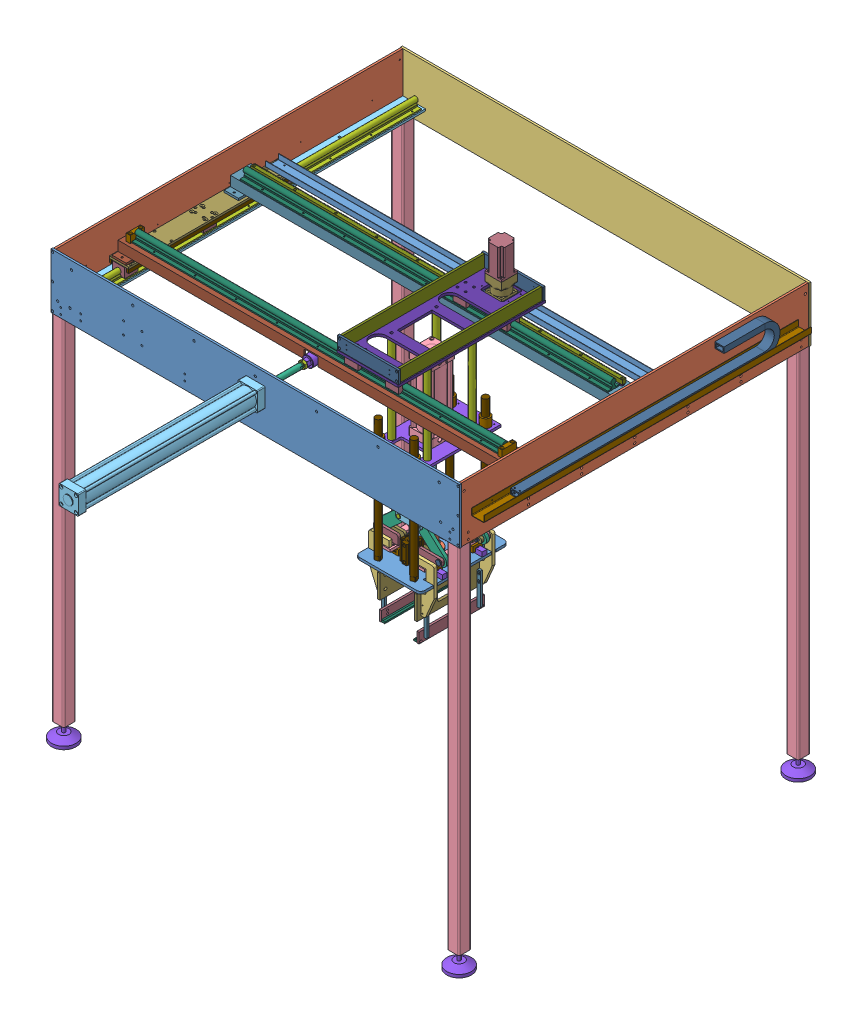
SolidWorks assembly 成品抓取排列机械手, configuration 默认. Lengths in mm.
Overall size (2113.16 2292 2692.16).
176 component instances, 69 part files, 126 mates.
Components (placement in the parent):
- 82-08-01  上线左右板-1: 82-08-01  上线左右板 [默认] at (-825.0477 550.6336 1800) size (2000 270 10)
- 82-08-02 上线前后板-2: 82-08-02 上线前后板 [默认] at (-1817.5477 550.6336 945) x (0 0 1) z (-1 0 0) size (1700 270 10)
- 82-08-03 上线左右板2-1: 82-08-03 上线左右板2 [默认] at (-825.0477 550.6336 90) x (-1 0 0) z (0 0 -1) size (2000 270 10)
- 82-08-13 支撑立柱1-1: 82-08-13 支撑立柱1 [默认<按加工>] at (-1792.5477 415.6336 115) x (0 0 1) z (1 0 0) size (60 1790 60)
- 82-08-13 支撑立柱1-3: 82-08-13 支撑立柱1 [默认<按加工>] at (142.4523 415.6336 115) x (-1 0 0) z (0 0 1) size (60 1790 60)
- 82-08-09 上线框架加强板-2: 82-08-09 上线框架加强板 [默认] at (112.4523 480.6336 945) x (0 0 -1) z (0 1 0) size (1700 110 10)
- 82-08-09 上线框架加强板-3: 82-08-09 上线框架加强板 [默认] at (-1762.5477 480.6336 945) x (0 0 1) z (0 1 0) size (1700 110 10)
- 82-08-02 上线前后板-3: 82-08-02 上线前后板 [默认] at (167.4523 550.6336 945) x (0 0 -1) z (1 0 0) size (1700 270 10)
- 82-08-05 加强筋板-12: 82-08-05 加强筋板 [默认] at (-1812.5477 475.6336 1465) x (-1 0 0) z (0 0 -1) size (60 60 10)
- 82-08-05 加强筋板-34: 82-08-05 加强筋板 [默认] at (162.4523 475.6336 1465) size (60 60 10)
- 滑轨SBR25 -1-1: 滑轨SBR25 -1 [默认] at (74.4286 478.9234 110) x (0 0 1) z (-1 0 0) size (1670 45.5 55)
- 滑轨SBR25 -1-2: 滑轨SBR25 -1 [默认] at (-1745.5714 478.9234 110) x (0 0 1) z (-1 0 0) size (1670 45.5 55)
- 调节脚Φ120-M16×165（YHBP20）-1: 调节脚Φ120-M16×165（YHBP20） [默认] at (142.4523 -1394.3664 115) x (0.999992 0 0.003912) z (-0.003912 0 0.999992) size (120 200 120)
- 调节脚Φ120-M16×165（YHBP20）-2: 调节脚Φ120-M16×165（YHBP20） [默认] at (-1792.5477 -1394.3664 115) x (0.791621 0 -0.611013) z (0.611013 0 0.791621) size (120 200 120)
- 82-08-04 坦克链线槽1-1: 82-08-04 坦克链线槽1 [默认] at (204.4523 525.6336 945) x (1 0 0) z (0 -1 0) size (64 1600 32)
- 20坦克链-2: 20坦克链 [默认] at (203.8418 539.6336 1561.8399) x (0 0 -1) z (1 0 0) size (1274 148 45)
- 82-08-14 槽钢支架1-1: 82-08-14 槽钢支架1 [默认<按加工>] at (-825.0477 613.6336 1532.1451) size (1890 58 160)
- 82-08-10 左右连接板-1: 82-08-10 左右连接板 [默认] at (-1735.0477 550.6336 1147.1451) x (1 0 0) z (0 1 0) size (95 830 10.21)
- SBR25-滑块-11: SBR25-滑块 [默认] at (-1735.0477 498.6336 1532.1451) size (60 47 65)
- SBR25-滑块-12: SBR25-滑块 [默认] at (-1735.0477 498.6336 1147.1451) size (60 47 65)
- SBR25-滑块-13: SBR25-滑块 [默认] at (-1735.0477 498.6336 762.1451) size (60 47 65)
- 82-08-10 左右连接板-2: 82-08-10 左右连接板 [默认] at (84.9523 550.6336 1147.1451) x (1 0 0) z (0 1 0) size (95 830 10.21)
- SBR25-滑块-14: SBR25-滑块 [默认] at (84.9523 498.6336 1532.1451) x (-1 0 0) z (0 0 -1) size (60 47 65)
- SBR25-滑块-15: SBR25-滑块 [默认] at (84.9523 498.6336 1147.1451) x (-1 0 0) z (0 0 -1) size (60 47 65)
- SBR25-滑块-16: SBR25-滑块 [默认] at (84.9523 498.6336 762.1451) x (-1 0 0) z (0 0 -1) size (60 47 65)
- 82-08-15 槽钢支架2-1: 82-08-15 槽钢支架2 [默认<按加工>] at (-825.0477 613.6336 982.1451) size (1890 58 160)
- 滑轨SBR25-2-3: 滑轨SBR25-2 [默认] at (-1725.0477 606.9234 962.6688) size (1800 45.5 55)
- 滑轨SBR25-2-4: 滑轨SBR25-2 [默认] at (-1725.0477 606.9234 1492.6688) size (1800 45.5 55)
- 82-06-00-200机械手装配体-翻转前抓取1-2: 82-06-00-200机械手装配体-翻转前抓取1 [默认] at (-1138.3737 644.7541 1170.3657) x (0 0 -1) z (1 0 0) size (720 1262.5 374.38)
  - 82-06-01  直线滑块固定板-1: 82-06-01  直线滑块固定板 [默认] at (-1.7794 70.8795 450) size (696 60 10)
  - 82-06-03  移动主板3-1: 82-06-03  移动主板3 [默认] at (-1.7794 34.8795 590) x (-1 0 0) z (0 1 0) size (720 300 12)
  - 82-06-17  抓取导向杆3-1: 82-06-17  抓取导向杆3 [默认] at (-221.7794 -585.1205 502.5) x (0 1 0) z (0.328486 0 0.944509) size (630 30 30)
  - 82-06-17  抓取导向杆3-2: 82-06-17  抓取导向杆3 [默认] at (-221.7794 -585.1205 677.5) x (0 1 0) z (0.328486 0 0.944509) size (630 30 30)
  - 82-06-17  抓取导向杆3-3: 82-06-17  抓取导向杆3 [默认] at (128.2206 -585.1205 502.5) x (0 1 0) z (0.328486 0 0.944509) size (630 30 30)
  - 82-06-17  抓取导向杆3-4: 82-06-17  抓取导向杆3 [默认] at (128.2206 -585.1205 677.5) x (0 1 0) z (0.328486 0 0.944509) size (630 30 30)
  - 82-06-14 抓取气缸固定板-1: 82-06-14 抓取气缸固定板 [默认] at (-46.7794 -891.1205 590) x (1 0 0) z (0 -1 0) size (430 320 12)
  - 82-06-06 升降连接法兰-1: 82-06-06 升降连接法兰 [默认] at (-46.7794 -707.1205 590) x (0 -1 0) z (-1 0 0) size (178 90 90)
  - 82-06-11  抓取气缸筋板-4: 82-06-11  抓取气缸筋板 [默认] at (95.7206 -837.1205 649.3691) x (0 0 1) z (-1 0 0) size (100 240 15)
  - 82-06-13  夹板连接板-1: 82-06-13  夹板连接板 [默认] at (-46.7794 -849.1205 674.3691) x (1 0 0) z (0 1 0) size (310 70 12)
  - 82-06-09 横梁块-1: 82-06-09 横梁块 [默认] at (50.7206 -711.1205 590) x (0 0 1) z (0 -1 0) size (120 40 30)
  - 82-06-07 抓取连接板-1: 82-06-07 抓取连接板 [默认] at (43.2206 -760.1205 688.4345) x (0 -0.675862 0.737028) z (1 0 0) size (195 50 15)
  - 82-06-19 上拉杆-1: 82-06-19 上拉杆 [默认] at (73.7206 -711.1205 635) x (-1 0 0) z (0 -0.924225 -0.381849) size (43 17 17)
  - 82-06-07 抓取连接板-3: 82-06-07 抓取连接板 [默认] at (43.2206 -760.1205 491.5655) x (0 -0.675862 -0.737028) z (1 0 0) size (195 50 15)
  - 82-06-11  抓取气缸筋板-6: 82-06-11  抓取气缸筋板 [默认] at (95.7206 -837.1205 530.6309) x (0 0 -1) z (1 0 0) size (100 240 15)
  - 82-06-13  夹板连接板-2: 82-06-13  夹板连接板 [默认] at (-46.7794 -837.1205 505.6309) x (1 0 0) z (0 -1 0) size (310 70 12)
  - 82-06-19 上拉杆-2: 82-06-19 上拉杆 [默认] at (73.7206 -711.1205 545) x (-1 0 0) z (0 -0.924225 0.381849) size (43 17 17)
  - 82-06-11  抓取气缸筋板-9: 82-06-11  抓取气缸筋板 [默认] at (-189.2794 -837.1205 649.3691) x (0 0 1) z (-1 0 0) size (100 240 15)
  - 82-06-07 抓取连接板-4: 82-06-07 抓取连接板 [默认] at (-136.7794 -760.1205 688.4345) x (0 0.675862 -0.737028) z (-1 0 0) size (195 50 15)
  - 82-06-07 抓取连接板-5: 82-06-07 抓取连接板 [默认] at (-136.7794 -760.1205 491.5655) x (0 0.675862 0.737028) z (-1 0 0) size (195 50 15)
  - 82-06-11  抓取气缸筋板-8: 82-06-11  抓取气缸筋板 [默认] at (-189.2794 -837.1205 530.6309) x (0 0 -1) z (1 0 0) size (100 240 15)
  - 82-06-09 横梁块-2: 82-06-09 横梁块 [默认] at (-144.2794 -711.1205 590) x (0 0 1) z (0 1 0) size (120 40 30)
  - 82-06-19 上拉杆-3: 82-06-19 上拉杆 [默认] at (-167.2794 -711.1205 635) x (1 0 0) z (0 -0.924225 -0.381849) size (43 17 17)
  - 82-06-19 上拉杆-4: 82-06-19 上拉杆 [默认] at (-167.2794 -711.1205 545) x (1 0 0) z (0 -0.924225 0.381849) size (43 17 17)
  - 00-HGW25滑轨长125-1: 00-HGW25滑轨长125 [默认] at (50.7206 -874.1205 750) x (0 0 -1) z (1 0 0) size (125 22 23)
  - 00-HGW25滑块-1: 00-HGW25滑块 [默认] at (50.7206 -850.1205 674.3691) size (70 29.5 84)
  - 82-06-12  拉杆-1: 82-06-12  拉杆 [默认] at (75.2206 -809.1205 741.8691) x (-1 0 0) z (0 -0.506926 -0.86199) size (58 22 22)
  - 82-06-12  拉杆-2: 82-06-12  拉杆 [默认] at (75.2206 -809.1205 438.1309) x (-1 0 0) z (0 -0.506926 0.86199) size (58 22 22)
  - 00-镜向HGW25滑轨长115-2: 00-镜向HGW25滑轨长115 [默认] at (50.7206 -874.1205 430) x (0 0 1) z (-1 0 0) size (125 22 23)
  - 00-HGW25滑块-2: 00-HGW25滑块 [默认] at (50.7206 -850.1205 505.6309) size (70 29.5 84)
  - 00-HGW25滑块-3: 00-HGW25滑块 [默认] at (-144.2794 -850.1205 674.3691) x (-1 0 0) z (0 0 -1) size (70 29.5 84)
  - 00-HGW25滑轨长125-3: 00-HGW25滑轨长125 [默认] at (-144.2794 -874.1205 750) x (0 0 -1) z (1 0 0) size (125 22 23)
  - 82-06-12  拉杆-3: 82-06-12  拉杆 [默认] at (-168.7794 -809.1205 741.8691) x (1 0 0) z (0 -0.506926 -0.86199) size (58 22 22)
  - 82-06-12  拉杆-4: 82-06-12  拉杆 [默认] at (-168.7794 -809.1205 438.1309) x (1 0 0) z (0 -0.506926 0.86199) size (58 22 22)
  - 00-HGW25滑块-4: 00-HGW25滑块 [默认] at (-144.2794 -850.1205 505.6309) x (-1 0 0) z (0 0 -1) size (70 29.5 84)
  - 00-镜向HGW25滑轨长115-4: 00-镜向HGW25滑轨长115 [默认] at (-144.2794 -874.1205 430) x (0 0 1) z (-1 0 0) size (125 22 23)
  - 82-06-08 滑块转角锁板-1: 82-06-08 滑块转角锁板 [默认] at (35.2206 -837.1205 636.8691) x (0 0 1) z (-1 0 0) size (120 40 12)
  - 82-06-18 滑块转角前锁板-1: 82-06-18 滑块转角前锁板 [默认] at (66.2206 -837.1205 636.8691) x (0 0 1) z (-1 0 0) size (120 44 12)
  - 82-06-08 滑块转角锁板-3: 82-06-08 滑块转角锁板 [默认] at (35.2206 -837.1205 543.1309) x (0 0 -1) z (1 0 0) size (120 40 12)
  - 82-06-18 滑块转角前锁板-2: 82-06-18 滑块转角前锁板 [默认] at (66.2206 -837.1205 543.1309) x (0 0 -1) z (1 0 0) size (120 44 12)
  - 82-06-18 滑块转角前锁板-3: 82-06-18 滑块转角前锁板 [默认] at (-159.7794 -837.1205 636.8691) x (0 0 1) z (-1 0 0) size (120 44 12)
  - 82-06-08 滑块转角锁板-4: 82-06-08 滑块转角锁板 [默认] at (-128.7794 -837.1205 636.8691) x (0 0 1) z (-1 0 0) size (120 40 12)
  - 82-06-18 滑块转角前锁板-4: 82-06-18 滑块转角前锁板 [默认] at (-159.7794 -837.1205 543.1309) x (0 0 -1) z (1 0 0) size (120 44 12)
  - 82-06-08 滑块转角锁板-5: 82-06-08 滑块转角锁板 [默认] at (-128.7794 -837.1205 543.1309) x (0 0 -1) z (1 0 0) size (120 40 12)
  - 00-ACQ50x50SB(0)+()-1: 00-ACQ50x50SB(0)+() [默认] at (50.7206 -794.6205 590) x (0 -1 0) z (1 0 0) size (174 64 71) (flexible)
    - 00-ACQS-50x5050_b-1: 00-ACQS-50x5050_b [默认] x (1 0 0) z (0 -1 0) size (90.5 71 64)
    - 00-ACQS-50x50-B_50r-1: 00-ACQS-50x50-B_50r [默认] at (-50 0 0) size (115 50 50)
    - 00-ACQ 50_Nut-1: 00-ACQ 50_Nut [默认] at (-57.5 0 0) x (-1 0 0) z (0 0.341797 -0.939774) size (11 34.29 27)
  - 82-06-10 上拉杆隔套-5: 82-06-10 上拉杆隔套 [默认] at (55.7206 -711.1205 635) x (0 0.442922 0.89656) z (1 0 0) size (18 18 3)
  - 82-06-10 上拉杆隔套-6: 82-06-10 上拉杆隔套 [默认] at (-152.2794 -711.1205 635) x (0 0.442922 0.89656) z (1 0 0) size (18 18 3)
  - 82-06-10 上拉杆隔套-7: 82-06-10 上拉杆隔套 [默认] at (58.7206 -711.1205 545) x (0 0.442922 -0.89656) z (-1 0 0) size (18 18 3)
  - 82-06-10 上拉杆隔套-8: 82-06-10 上拉杆隔套 [默认] at (-149.2794 -711.1205 545) x (0 0.442922 -0.89656) z (-1 0 0) size (18 18 3)
  - 镜向00-ACQ50x50SB(0)+()-3: 镜向00-ACQ50x50SB(0)+() [默认] at (-144.2794 -794.6205 590) x (0 -1 0) z (1 0 0) size (174 64 71) (flexible)
    - 镜向00-ACQS-50x5050_b-1: 镜向00-ACQS-50x5050_b [默认] x (1 0 0) z (0 1 0) size (90.5 71 64)
    - 镜向00-ACQS-50x50-B_50r-1: 镜向00-ACQS-50x50-B_50r [默认] at (-50 0 0) size (115 50 50)
    - 镜向00-ACQ 50_Nut-1: 镜向00-ACQ 50_Nut [默认] at (-57.5 0 0) x (-1 0 0) z (0 -0.341797 -0.939774) size (11 34.29 27)
  - GB／T276-94深沟球轴承6201-2Z-1: GB／T276-94深沟球轴承6201-2Z [默认] at (50.7206 -809.1205 438.1309) x (1 0 0) z (0 0.587051 -0.80955) size (10 32 32)
  - GB／T276-94深沟球轴承6201-2Z-2: GB／T276-94深沟球轴承6201-2Z [默认] at (-144.2794 -809.1205 438.1309) x (1 0 0) z (0 0.353964 0.935259) size (10 32 32)
  - JSI100x250S(000)+()-2: JSI100x250S(000)+() [默认] at (-46.7794 -405.1205 590) x (0 1 0) z (0 0 1) size (690 114 114)
    - JSI-100x250-S- (0) c-1: JSI-100x250-S- (0) c [默认] at origin size (388 114 114)
    - JSI JSID JSIJ POLE 100JSI2500-1: JSI JSID JSIJ POLE 100JSI2500 [默认] at (-270 0 0) x (0 0 -1) z (-1 0 0) size (99 99 401)
    - JSI-100-M26x1_5 - Nut-1: JSI-100-M26x1_5 - Nut [默认] at (-302 0 0) size (13 41.57 36)
  - 82-06-04 气缸支撑杆-1: 82-06-04 气缸支撑杆 [默认] at (63.2206 -188.1205 677.5) x (0.271774 0 0.962361) z (0 1 0) size (30 30 434)
  - 82-06-04 气缸支撑杆-4: 82-06-04 气缸支撑杆 [默认] at (63.2206 -188.1205 502.5) x (-0.824959 0 0.565193) z (0 1 0) size (30 30 434)
  - 82-06-05 二层导向板2-1: 82-06-05 二层导向板2 [默认] at (-46.7794 -411.1205 590) x (1 0 0) z (0 1 0) size (430 245 12)
  - 82-06-04 气缸支撑杆-5: 82-06-04 气缸支撑杆 [默认] at (-156.7794 -188.1205 677.5) x (-0.271774 0 0.962361) z (0 -1 0) size (30 30 434)
  - 82-06-04 气缸支撑杆-6: 82-06-04 气缸支撑杆 [默认] at (-156.7794 -188.1205 502.5) x (0.824959 0 0.565193) z (0 -1 0) size (30 30 434)
  - 直线轴承LMH-30UU-11: 直线轴承LMH-30UU [默认] at (-221.7794 -427.1205 502.5) x (0 1 0) z (0 0 1) size (64 74 51)
  - 直线轴承LMH-30UU-12: 直线轴承LMH-30UU [默认] at (128.2206 -427.1205 502.5) x (0 1 0) z (0 0 1) size (64 74 51)
  - 直线轴承LMH-30UU-13: 直线轴承LMH-30UU [默认] at (-221.7794 -427.1205 677.5) x (0 1 0) z (0 0 1) size (64 74 51)
  - 直线轴承LMH-30UU-14: 直线轴承LMH-30UU [默认] at (128.2206 -427.1205 677.5) x (0 1 0) z (0 0 1) size (64 74 51)
  - 盖子（120AH）-1: 盖子（120AH） [默认] at (-250.2794 -1134.1205 503.5) x (1 0 0) z (0 -1 0) size (407 173 55.85) (hidden)
  - 00-电池壳120-2: 00-电池壳120 [默认] at (155.7206 -1149.1205 503.5) x (-1 0 0) z (0 1 0) size (405 173 190) (hidden)
  - 82-06-02 位移左端板-3: 82-06-02 位移左端板 [默认] at (-354.7794 100.8795 740) x (0 0 -1) z (1 0 0) size (300 60 10)
  - 82-06-01  直线滑块固定板-2: 82-06-01  直线滑块固定板 [默认] at (-1.7794 70.8795 730) size (696 60 10)
  - 82-06-02 位移左端板-4: 82-06-02 位移左端板 [默认] at (351.2206 100.8795 440) x (0 0 1) z (-1 0 0) size (300 60 10)
  - GB／T276-94深沟球轴承6201-2Z-3: GB／T276-94深沟球轴承6201-2Z [默认] at (50.7206 -711.1205 635) size (10 32 32)
  - 82-06-10 上拉杆隔套-9: 82-06-10 上拉杆隔套 [默认] at (42.7206 -711.1205 635) x (0 0.909511 -0.41568) z (1 0 0) size (18 18 3)
  - 82-06-10 上拉杆隔套-10: 82-06-10 上拉杆隔套 [默认] at (45.7206 -711.1205 545) x (0 0.909511 0.41568) z (-1 0 0) size (18 18 3)
  - GB／T276-94深沟球轴承6201-2Z-4: GB／T276-94深沟球轴承6201-2Z [默认] at (50.7206 -711.1205 545) size (10 32 32)
  - GB／T276-94深沟球轴承6201-2Z-5: GB／T276-94深沟球轴承6201-2Z [默认] at (-144.2794 -711.1205 635) x (-1 0 0) z (0 0 -1) size (10 32 32)
  - 82-06-10 上拉杆隔套-11: 82-06-10 上拉杆隔套 [默认] at (-139.2794 -711.1205 635) x (0 0.909511 -0.41568) z (1 0 0) size (18 18 3)
  - GB／T276-94深沟球轴承6201-2Z-6: GB／T276-94深沟球轴承6201-2Z [默认] at (-144.2794 -711.1205 545) x (-1 0 0) z (0 0 -1) size (10 32 32)
  - 82-06-10 上拉杆隔套-12: 82-06-10 上拉杆隔套 [默认] at (-136.2794 -711.1205 545) x (0 0.909511 0.41568) z (-1 0 0) size (18 18 3)
  - 82-06-20 上拉杆隔套2-1: 82-06-20 上拉杆隔套2 [默认] at (41.2206 -809.1205 438.1309) x (0 0.909511 -0.41568) z (1 0 0) size (18 18 4.5)
  - GB／T276-94深沟球轴承6201-2Z-7: GB／T276-94深沟球轴承6201-2Z [默认] at (50.7206 -809.1205 741.8691) x (1 0 0) z (0 -0.587051 -0.80955) size (10 32 32)
  - 82-06-20 上拉杆隔套2-2: 82-06-20 上拉杆隔套2 [默认] at (45.7206 -809.1205 741.8691) x (0 0.909511 0.41568) z (-1 0 0) size (18 18 4.5)
  - GB／T276-94深沟球轴承6201-2Z-8: GB／T276-94深沟球轴承6201-2Z [默认] at (-144.2794 -809.1205 741.8691) x (-1 0 0) z (0 0.587051 0.80955) size (10 32 32)
  - 82-06-20 上拉杆隔套2-3: 82-06-20 上拉杆隔套2 [默认] at (-134.7794 -809.1205 741.8691) x (0 0.909511 0.41568) z (-1 0 0) size (18 18 4.5)
  - GB／T276-94深沟球轴承6201-2Z-9: GB／T276-94深沟球轴承6201-2Z [默认] at (-144.2794 -809.1205 438.1309) x (-1 0 0) z (0 -0.587051 0.80955) size (10 32 32)
  - 82-06-20 上拉杆隔套2-4: 82-06-20 上拉杆隔套2 [默认] at (-139.2794 -809.1205 438.1309) x (0 0.909511 -0.41568) z (1 0 0) size (18 18 4.5)
  - 82-06-15  锁紧板2-1: 82-06-15  锁紧板2 [默认] at (-46.7794 -1004.6205 686.8691) x (-1 0 0) z (0 0 -1) size (340 115 12)
  - 82-06-21 夹壳定位块1-4: 82-06-21 夹壳定位块1 [默认] at (113.2206 -1161.6205 676.8691) x (0 0 1) z (-1 0 0) size (10 50 320)
  - 82-06-16 卡盖调节板-2: 82-06-16 卡盖调节板 [默认] at (-171.7794 -1147.1205 701.8691) x (0 1 0) z (-1 0 0) size (160 15 10)
  - 82-06-16 卡盖调节板-3: 82-06-16 卡盖调节板 [默认] at (88.2206 -1147.1205 701.8691) x (0 1 0) z (-1 0 0) size (160 15 10)
  - 82-06-16 卡盖调节板-4: 82-06-16 卡盖调节板 [默认] at (78.2206 -1147.1205 478.1309) x (0 1 0) z (1 0 0) size (160 15 10)
  - 82-06-16 卡盖调节板-5: 82-06-16 卡盖调节板 [默认] at (-181.7794 -1147.1205 478.1309) x (0 1 0) z (1 0 0) size (160 15 10)
  - 82-06-21 夹壳定位块1-5: 82-06-21 夹壳定位块1 [默认] at (-206.7794 -1161.6205 503.1309) x (0 0 -1) z (1 0 0) size (10 50 320)
  - 82-06-22 夹壳定位块2-3: 82-06-22 夹壳定位块2 [默认] at (113.2206 -1159.6205 676.8691) x (0 1 0) z (-1 0 0) size (10 16 320)
  - 82-06-22 夹壳定位块2-4: 82-06-22 夹壳定位块2 [默认] at (-206.7794 -1159.6205 503.1309) x (0 1 0) z (1 0 0) size (10 16 320)
  - 82-06-15  锁紧板2-3: 82-06-15  锁紧板2 [默认] at (-46.7794 -1004.6205 493.1309) size (340 115 12)
- SBR25-滑块-17: SBR25-滑块 [默认] at (-648.3737 626.6336 1482.1451) x (0 0 -1) z (1 0 0) size (60 47 65)
- SBR25-滑块-18: SBR25-滑块 [默认] at (-448.3737 626.6336 1482.1451) x (0 0 -1) z (1 0 0) size (60 47 65)
- SBR25-滑块-19: SBR25-滑块 [默认] at (-648.3737 626.6336 952.1451) x (0 0 -1) z (1 0 0) size (60 47 65)
- SBR25-滑块-20: SBR25-滑块 [默认] at (-448.3737 626.6336 952.1451) x (0 0 -1) z (1 0 0) size (60 47 65)
- 2M齿条2-1: 2M齿条2 [默认] at (-825.0477 620.1336 918.1451) x (0 1 0) z (-1 0 0) size (20 20 1820)
- 82-08-12 齿条垫圈-10: 82-08-12 齿条垫圈 [默认] at (74.9523 616.8836 911.1451) x (0.980798 0 -0.195024) z (0.195024 0 0.980798) size (18 6.5 18)
- 82-08-12 齿条垫圈-11: 82-08-12 齿条垫圈 [默认] at (-125.0477 616.8836 911.1451) x (0.980798 0 -0.195024) z (0.195024 0 0.980798) size (18 6.5 18)
- 82-08-12 齿条垫圈-12: 82-08-12 齿条垫圈 [默认] at (-325.0477 616.8836 911.1451) x (0.980798 0 -0.195024) z (0.195024 0 0.980798) size (18 6.5 18)
- 82-08-12 齿条垫圈-13: 82-08-12 齿条垫圈 [默认] at (-525.0477 616.8836 911.1451) x (0.980798 0 -0.195024) z (0.195024 0 0.980798) size (18 6.5 18)
- 82-08-12 齿条垫圈-14: 82-08-12 齿条垫圈 [默认] at (-725.0477 616.8836 911.1451) x (0.980798 0 -0.195024) z (0.195024 0 0.980798) size (18 6.5 18)
- 82-08-12 齿条垫圈-15: 82-08-12 齿条垫圈 [默认] at (-925.0477 616.8836 911.1451) x (0.980798 0 -0.195024) z (0.195024 0 0.980798) size (18 6.5 18)
- 82-08-12 齿条垫圈-16: 82-08-12 齿条垫圈 [默认] at (-1125.0477 616.8836 911.1451) x (0.980798 0 -0.195024) z (0.195024 0 0.980798) size (18 6.5 18)
- 82-08-12 齿条垫圈-17: 82-08-12 齿条垫圈 [默认] at (-1325.0477 616.8836 911.1451) x (0.980798 0 -0.195024) z (0.195024 0 0.980798) size (18 6.5 18)
- 82-08-12 齿条垫圈-18: 82-08-12 齿条垫圈 [默认] at (-1525.0477 616.8836 911.1451) x (0.980798 0 -0.195024) z (0.195024 0 0.980798) size (18 6.5 18)
- 82-08-12 齿条垫圈-19: 82-08-12 齿条垫圈 [默认] at (-1725.0477 616.8836 911.1451) x (0.980798 0 -0.195024) z (0.195024 0 0.980798) size (18 6.5 18)
- 82-08-11 左右连接加强板-1: 82-08-11 左右连接加强板 [默认] at (-1693.5477 536.6336 1147.1451) x (0 1 0) z (-1 0 0) size (18 830 11)
- 82-08-16 拖链折板-1: 82-08-16 拖链折板 [默认] at (-825.0477 557.6336 772.1451) x (0 0 1) z (-1 0 0) size (64 27 1900)
- 82-08-08 坦克链连接块-2: 82-08-08 坦克链连接块 [默认] at (-653.3737 732.6336 812.1451) x (0 -1 0) z (1 0 0) size (37 62 22)
- 82-08-11 左右连接加强板-2: 82-08-11 左右连接加强板 [默认] at (-1776.5477 536.6336 1147.1451) x (0 1 0) z (-1 0 0) size (18 830 11)
- 82-08-11 左右连接加强板-3: 82-08-11 左右连接加强板 [默认] at (43.4523 536.6336 1147.1451) x (0 1 0) z (-1 0 0) size (18 830 11)
- 82-08-11 左右连接加强板-4: 82-08-11 左右连接加强板 [默认] at (126.4523 536.6336 1147.1451) x (0 1 0) z (-1 0 0) size (18 830 11)
- 82-08-05 加强筋板-30: 82-08-05 加强筋板 [默认] at (-1812.5477 475.6336 1205) x (-1 0 0) z (0 0 -1) size (60 60 10)
- 82-08-05 加强筋板-31: 82-08-05 加强筋板 [默认] at (-1812.5477 475.6336 945) x (-1 0 0) z (0 0 -1) size (60 60 10)
- 82-08-05 加强筋板-32: 82-08-05 加强筋板 [默认] at (-1812.5477 475.6336 685) x (-1 0 0) z (0 0 -1) size (60 60 10)
- 82-08-05 加强筋板-33: 82-08-05 加强筋板 [默认] at (-1812.5477 475.6336 425) x (-1 0 0) z (0 0 -1) size (60 60 10)
- 82-08-05 加强筋板-35: 82-08-05 加强筋板 [默认] at (162.4523 475.6336 1205) size (60 60 10)
- 82-08-05 加强筋板-36: 82-08-05 加强筋板 [默认] at (162.4523 475.6336 945) size (60 60 10)
- 82-08-05 加强筋板-37: 82-08-05 加强筋板 [默认] at (162.4523 475.6336 685) size (60 60 10)
- 82-08-05 加强筋板-38: 82-08-05 加强筋板 [默认] at (162.4523 475.6336 425) size (60 60 10)
- 82-08-13 支撑立柱1-5: 82-08-13 支撑立柱1 [默认<按加工>] at (142.4523 415.6336 1775) x (0 0 -1) z (-1 0 0) size (60 1790 60)
- 82-08-13 支撑立柱1-6: 82-08-13 支撑立柱1 [默认<按加工>] at (-1792.5477 415.6336 1775) x (1 0 0) z (0 0 -1) size (60 1790 60)
- 调节脚Φ120-M16×165（YHBP20）-3: 调节脚Φ120-M16×165（YHBP20） [默认] at (142.4523 -1394.3664 1775) x (0.999992 0 -0.003912) z (0.003912 0 0.999992) size (120 200 120)
- 调节脚Φ120-M16×165（YHBP20）-4: 调节脚Φ120-M16×165（YHBP20） [默认] at (-1792.5477 -1394.3664 1775) x (0.791621 0 0.611013) z (-0.611013 0 0.791621) size (120 200 120)
- 82-08-17 前后加强侧板-1: 82-08-17 前后加强侧板 [默认] at (-825.0477 645.6336 1782.5) x (1 0 0) z (0 -1 0) size (1975 25 14)
- 82-08-07 齿轮连接头-1: 82-08-07 齿轮连接头 [默认] at (-548.3737 625.1336 877.1451) x (0 0 -1) z (-1 0 0) size (21 7.5 25)
- JSI80x800S(000)+()-1: JSI80x800S(000)+() [默认] at (-825.0477 578.6336 1805) x (0 0 1) z (-1 0 0) size (1177.35 95 95) (flexible)
  - JSI-80x800-S- (0) c-1: JSI-80x800-S- (0) c [默认] at origin size (938 95 95)
  - JSI JSID JSIJ POLE 80JSI8000-1: JSI JSID JSIJ POLE 80JSI8000 [默认] at (-207.3549 0 0) x (0 0 -1) z (-1 0 0) size (79 79 951.5)
  - JSI-80-M22x1_5 - Nut-1: JSI-80-M22x1_5 - Nut [默认] at (-239.3549 0 0) size (13 36.95 32)
- F-M22X150F-1: F-M22X150F [默认] at (-825.0477 578.6336 1457.6451) x (-0.195458 -0.980712 0) z (0 0 1) size (53 53 108)
- 82-08-18 限位挡块-1: 82-08-18 限位挡块 [默认] at (-1735.0477 631.1336 1482.1451) x (0 0 1) z (-1 0 0) size (70 35 20)
- 82-08-18 限位挡块-2: 82-08-18 限位挡块 [默认] at (84.9523 631.1336 1482.1451) x (0 0 1) z (-1 0 0) size (70 35 20)
- 82-08-06 电机安装板2-1: 82-08-06 电机安装板2 [默认] at (-548.3737 668.6336 877.1451) x (0 0 1) z (0 -1 0) size (90 150 10)
- 82-08-19 圆柱齿轮23×2-3: 82-08-19 圆柱齿轮23×2 [默认] at (-548.3737 620.1336 877.1451) x (-0.457191 0 -0.889369) z (0 1 0) size (49.96 49.85 35)
- FA80-10 利明减速机-1: FA80-10 利明减速机 [默认] at (-548.3737 757.6336 877.1451) x (1 0 0) z (0 -1 0) size (80 80 132.5)
- JSMA-SC08ABA01-1: JSMA-SC08ABA01 [默认] at (-548.3737 757.6336 877.1451) x (1 0 0) z (0 1 0) size (80 80 140)
Mates (geometry in assembly coordinates):
- 同心3: concentric aligned: cylinder of 82-08-01  上线左右板-1 through (-1817.5477 675.6336 1805) axis (0 0 1) radius 3.3; cylinder of 82-08-02 上线前后板-2 through (-1817.5477 675.6336 1795) axis (0 0 1) radius 2.5
- 重合2: coincident anti-aligned: plane of 82-08-01  上线左右板-1 through (-825.0477 550.6336 1795) normal (0 0 -1); plane of 82-08-02 上线前后板-2 through (-1822.5477 415.6336 1795) normal (0 0 1)
- 重合3: coincident anti-aligned: plane of 82-08-02 上线前后板-2 through (-1822.5477 415.6336 95) normal (0 0 -1); plane of 82-08-03 上线左右板2-1 through (-825.0477 550.6336 95) normal (0 0 1)
- 同心5: concentric aligned: cylinder of 82-08-02 上线前后板-2 through (-1817.5477 675.6336 95) axis (0 0 -1) radius 2.5; cylinder of 82-08-03 上线左右板2-1 through (-1817.5477 675.6336 85) axis (0 0 -1) radius 3.3
- 同心27: concentric aligned: cylinder of 82-08-01  上线左右板-1 through (-1817.5477 425.6336 1805) axis (0 0 1) radius 5.5; circle of 82-08-02 上线前后板-2
- 重合92: coincident anti-aligned: plane of 82-08-01  上线左右板-1 through (-825.0477 550.6336 1795) normal (0 0 -1); plane of 82-08-09 上线框架加强板-2 through (162.4523 485.6336 1795) normal (0 0 1)
- 重合93: coincident anti-aligned: plane of 82-08-02 上线前后板-2 through (-1812.5477 550.6336 945) normal (1 0 0); plane of 82-08-09 上线框架加强板-3 through (-1812.5477 485.6336 95) normal (-1 0 0)
- 同心100: concentric aligned: cylinder of 82-08-03 上线左右板2-1 through (167.4523 425.6336 85) axis (0 0 -1) radius 3.3; cylinder of 82-08-02 上线前后板-3 through (167.4523 425.6336 95) axis (0 0 -1) radius 2.5
- 重合95: coincident anti-aligned: plane of 82-08-03 上线左右板2-1 through (-825.0477 550.6336 95) normal (0 0 1); plane of 82-08-02 上线前后板-3 through (172.4523 415.6336 95) normal (0 0 -1)
- 同心101: concentric aligned: cylinder of 82-08-03 上线左右板2-1 through (167.4523 675.6336 85) axis (0 0 -1) radius 5.5; cylinder of 82-08-02 上线前后板-3 through (167.4523 675.6336 95) axis (0 0 -1) radius 2.5
- 同心102: concentric aligned: cylinder of 82-08-03 上线左右板2-1 through (167.4523 550.6336 85) axis (0 0 -1) radius 5.5; cylinder of 82-08-02 上线前后板-3 through (167.4523 550.6336 95) axis (0 0 -1) radius 2.5
- 同心103: concentric aligned: cylinder of 82-08-01  上线左右板-1 through (167.4523 675.6336 1805) axis (0 0 1) radius 5.5; circle of 82-08-02 上线前后板-3
- 重合101: coincident anti-aligned: plane of 82-08-02 上线前后板-2 through (-1812.5477 550.6336 945) normal (1 0 0); plane of 82-08-05 加强筋板-12 through (-1812.5477 415.6336 1460) normal (-1 0 0)
- 重合103: coincident anti-aligned: plane of 82-08-02 上线前后板-3 through (162.4523 550.6336 945) normal (-1 0 0); plane of 82-08-05 加强筋板-34 through (162.4523 415.6336 1470) normal (1 0 0)
- 重合104: coincident anti-aligned: plane of 82-08-09 上线框架加强板-2 through (112.4523 475.6336 945) normal (0 -1 0); plane of 82-08-05 加强筋板-34 through (162.4523 475.6336 1470) normal (0 1 0)
- 重合173: coincident anti-aligned: plane of 82-08-09 上线框架加强板-2 through (112.4523 485.6336 945) normal (0 1 0); plane of 滑轨SBR25 -1-1 through (112.4523 485.6336 1780) normal (0 -1 0)
- 重合227: coincident anti-aligned: plane of 82-08-09 上线框架加强板-3 through (-1762.5477 485.6336 945) normal (0 1 0); plane of 滑轨SBR25 -1-2 through (-1707.5477 485.6336 1780) normal (0 -1 0)
- 同心297: concentric aligned: cylinder of 82-08-09 上线框架加强板-3 through (-1752.5477 485.6336 1745) axis (0 1 0) radius 2.5; cylinder of 滑轨SBR25 -1-2 through (-1752.5477 491.6336 1745) axis (0 1 0) radius 3.3
- 同心298: concentric aligned: cylinder of 82-08-09 上线框架加强板-2 through (67.4523 485.6336 145) axis (0 1 0) radius 2.5; cylinder of 滑轨SBR25 -1-1 through (67.4523 491.6336 145) axis (0 1 0) radius 3.3
- 重合238: coincident aligned: plane of 调节脚Φ120-M16×165（YHBP20）-1 through (142.4523 -1394.3664 115) normal (0 -1 0); plane of 调节脚Φ120-M16×165（YHBP20）-2 through (-1792.5477 -1394.3664 115) normal (0 -1 0)
- 重合252: coincident anti-aligned: plane of 82-08-02 上线前后板-3 through (172.4523 550.6336 945) normal (1 0 0); plane of 82-08-04 坦克链线槽1-1 through (172.4523 555.6336 1745) normal (-1 0 0)
- 同心329: concentric anti-aligned: circle of 82-08-02 上线前后板-3; cylinder of 82-08-04 坦克链线槽1-1 through (172.4523 540.6336 1645) axis (-1 0 0) radius 2.75
- 同心330: concentric anti-aligned: cylinder of 82-08-02 上线前后板-3 through (172.4523 540.6336 1295) axis (1 0 0) radius 2.1; circle of 82-08-04 坦克链线槽1-1
- 重合253: coincident anti-aligned: plane of 82-08-04 坦克链线槽1-1 through (177.4523 525.6336 1745) normal (0 1 0); plane of 20坦克链-2 through (226.3418 525.6336 1561.8399) normal (0 -1 0)
- 同心337: concentric aligned: cylinder of 滑轨SBR25 -1-2 through (-1735.0477 518.6336 1780) axis (0 0 -1) radius 12.5; cylinder of SBR25-滑块-11 through (-1735.0477 518.6336 1564.6451) axis (0 0 -1) radius 12.5
- 重合256: coincident anti-aligned: plane of 82-08-10 左右连接板-1 through (-1735.0477 545.6336 1147.1451) normal (0 -1 0); plane of SBR25-滑块-11 through (-1765.0477 545.6336 1564.6451) normal (0 1 0)
- 同心338: concentric aligned: cylinder of 82-08-10 左右连接板-1 through (-1755.0477 555.6336 1552.1451) axis (0 1 0) radius 3.3; cylinder of SBR25-滑块-11 through (-1755.0477 545.6336 1552.1451) axis (0 1 0) radius 2.5
- 同心339: concentric aligned: cylinder of 82-08-10 左右连接板-1 through (-1715.0477 555.6336 1512.1451) axis (0 1 0) radius 3.3; cylinder of SBR25-滑块-11 through (-1715.0477 545.6336 1512.1451) axis (0 1 0) radius 2.5
- 平行12: parallel aligned: plane of 滑轨SBR25 -1-2 through (-1707.5477 491.6336 1780) normal (0 1 0); plane of 82-08-10 左右连接板-1 through (-1735.0477 555.6336 1147.1451) normal (0 1 0)
- 同心340: concentric aligned: cylinder of 滑轨SBR25 -1-2 through (-1735.0477 518.6336 1780) axis (0 0 -1) radius 12.5; cylinder of SBR25-滑块-12 through (-1735.0477 518.6336 1179.6451) axis (0 0 -1) radius 12.5
- 同心341: concentric aligned: cylinder of 82-08-10 左右连接板-1 through (-1755.0477 555.6336 1167.1451) axis (0 1 0) radius 5.5; cylinder of SBR25-滑块-12 through (-1755.0477 545.6336 1167.1451) axis (0 1 0) radius 2.5
- 重合258: coincident anti-aligned: plane of 82-08-10 左右连接板-1 through (-1735.0477 545.6336 1147.1451) normal (0 -1 0); plane of SBR25-滑块-13 through (-1765.0477 545.6336 794.6451) normal (0 1 0)
- 同心342: concentric aligned: cylinder of 82-08-10 左右连接板-1 through (-1715.0477 555.6336 782.1451) axis (0 1 0) radius 3.3; cylinder of SBR25-滑块-13 through (-1715.0477 545.6336 782.1451) axis (0 1 0) radius 2.5
- 同心343: concentric aligned: cylinder of 82-08-10 左右连接板-1 through (-1755.0477 555.6336 742.1451) axis (0 1 0) radius 3.3; cylinder of SBR25-滑块-13 through (-1755.0477 545.6336 742.1451) axis (0 1 0) radius 2.5
- 重合259: coincident anti-aligned: plane of 82-08-14 槽钢支架1-1 through (-825.0477 555.6336 1532.1451) normal (0 -1 0); plane of 82-08-10 左右连接板-1 through (-1735.0477 555.6336 1147.1451) normal (0 1 0)
- 同心344: concentric aligned: cylinder of 82-08-14 槽钢支架1-1 through (-1735.0477 565.6336 1547.1451) axis (0 1 0) radius 4.5; cylinder of 82-08-10 左右连接板-1 through (-1735.0477 555.6336 1547.1451) axis (0 1 0) radius 3.4
- 同心345: concentric aligned: cylinder of 82-08-14 槽钢支架1-1 through (-1735.0477 565.6336 1417.1451) axis (0 1 0) radius 4.5; cylinder of 82-08-10 左右连接板-1 through (-1735.0477 555.6336 1417.1451) axis (0 1 0) radius 3.4
- 重合261: coincident anti-aligned: plane of 82-08-15 槽钢支架2-1 through (119.9523 613.6336 982.1451) normal (0 1 0); plane of 滑轨SBR25-2-3 through (74.9523 613.6336 959.6451) normal (0 -1 0)
- 同心348: concentric aligned: cylinder of 82-08-15 槽钢支架2-1 through (-1625.0477 613.6336 969.6451) axis (0 1 0) radius 2.5; circle of 滑轨SBR25-2-3
- 同心349: concentric aligned: cylinder of 82-08-15 槽钢支架2-1 through (-1425.0477 613.6336 934.6451) axis (0 1 0) radius 2.5; cylinder of 滑轨SBR25-2-3 through (-1425.0477 619.6336 934.6451) axis (0 1 0) radius 3.3
- 重合262: coincident anti-aligned: plane of 82-08-14 槽钢支架1-1 through (119.9523 613.6336 1532.1451) normal (0 1 0); plane of 滑轨SBR25-2-4 through (74.9523 613.6336 1489.6451) normal (0 -1 0)
- 同心350: concentric aligned: cylinder of 82-08-14 槽钢支架1-1 through (-1625.0477 613.6336 1464.6451) axis (0 1 0) radius 2.5; cylinder of 滑轨SBR25-2-4 through (-1625.0477 619.6336 1464.6451) axis (0 1 0) radius 3.3
- 同心351: concentric aligned: cylinder of 82-08-14 槽钢支架1-1 through (-1425.0477 613.6336 1499.6451) axis (0 1 0) radius 2.5; cylinder of 滑轨SBR25-2-4 through (-1425.0477 619.6336 1499.6451) axis (0 1 0) radius 3.3
- 重合263: coincident anti-aligned: plane of 82-06-00-200机械手装配体-翻转前抓取1-2/82-06-03  移动主板3-1 through (-548.3737 673.6336 1172.1451) normal (0 -1 0); plane of SBR25-滑块-17 through (-615.8737 673.6336 1512.1451) normal (0 1 0)
- 同心352: concentric aligned: cylinder of 82-06-00-200机械手装配体-翻转前抓取1-2/82-06-03  移动主板3-1 through (-668.3737 685.6336 1502.1451) axis (0 1 0) radius 3.3; cylinder of SBR25-滑块-17 through (-668.3737 673.6336 1502.1451) axis (0 1 0) radius 2.5
- 同心353: concentric aligned: cylinder of 82-06-00-200机械手装配体-翻转前抓取1-2/82-06-03  移动主板3-1 through (-628.3737 685.6336 1462.1451) axis (0 1 0) radius 3.3; cylinder of SBR25-滑块-17 through (-628.3737 673.6336 1462.1451) axis (0 1 0) radius 2.5
- 重合265: coincident anti-aligned: plane of 82-06-00-200机械手装配体-翻转前抓取1-2/82-06-03  移动主板3-1 through (-548.3737 673.6336 1172.1451) normal (0 -1 0); plane of SBR25-滑块-19 through (-615.8737 673.6336 982.1451) normal (0 1 0)
- 同心354: concentric aligned: cylinder of 82-06-00-200机械手装配体-翻转前抓取1-2/82-06-03  移动主板3-1 through (-668.3737 685.6336 972.1451) axis (0 1 0) radius 5.5; cylinder of SBR25-滑块-19 through (-668.3737 673.6336 972.1451) axis (0 1 0) radius 2.5
- 同心355: concentric aligned: cylinder of 82-06-00-200机械手装配体-翻转前抓取1-2/82-06-03  移动主板3-1 through (-628.3737 685.6336 932.1451) axis (0 1 0) radius 5.5; cylinder of SBR25-滑块-19 through (-628.3737 673.6336 932.1451) axis (0 1 0) radius 2.5
- 重合266: coincident anti-aligned: plane of 82-06-00-200机械手装配体-翻转前抓取1-2/82-06-03  移动主板3-1 through (-548.3737 673.6336 1172.1451) normal (0 -1 0); plane of SBR25-滑块-20 through (-415.8737 673.6336 982.1451) normal (0 1 0)
- 同心356: concentric aligned: circle of 82-06-00-200机械手装配体-翻转前抓取1-2/82-06-03  移动主板3-1; cylinder of SBR25-滑块-20 through (-468.3737 673.6336 972.1451) axis (0 1 0) radius 2.5
- 同心357: concentric aligned: cylinder of 82-06-00-200机械手装配体-翻转前抓取1-2/82-06-03  移动主板3-1 through (-428.3737 685.6336 932.1451) axis (0 1 0) radius 3.3; cylinder of SBR25-滑块-20 through (-428.3737 673.6336 932.1451) axis (0 1 0) radius 2.5
- 重合267: coincident anti-aligned: plane of 82-06-00-200机械手装配体-翻转前抓取1-2/82-06-03  移动主板3-1 through (-548.3737 673.6336 1172.1451) normal (0 -1 0); plane of SBR25-滑块-18 through (-415.8737 673.6336 1512.1451) normal (0 1 0)
- 同心358: concentric aligned: cylinder of 82-06-00-200机械手装配体-翻转前抓取1-2/82-06-03  移动主板3-1 through (-468.3737 685.6336 1502.1451) axis (0 1 0) radius 3.3; cylinder of SBR25-滑块-18 through (-468.3737 673.6336 1502.1451) axis (0 1 0) radius 2.5
- 同心359: concentric aligned: cylinder of 82-06-00-200机械手装配体-翻转前抓取1-2/82-06-03  移动主板3-1 through (-428.3737 685.6336 1462.1451) axis (0 1 0) radius 3.3; cylinder of SBR25-滑块-18 through (-428.3737 673.6336 1462.1451) axis (0 1 0) radius 2.5
- 同心360: concentric aligned: cylinder of 滑轨SBR25-2-3 through (74.9523 646.6336 952.1451) axis (-1 0 0) radius 12.5; cylinder of SBR25-滑块-19 through (-615.8737 646.6336 952.1451) axis (-1 0 0) radius 12.5
- 同心361: concentric aligned: cylinder of 滑轨SBR25-2-4 through (74.9523 646.6336 1482.1451) axis (-1 0 0) radius 12.5; cylinder of SBR25-滑块-17 through (-615.8737 646.6336 1482.1451) axis (-1 0 0) radius 12.5
- 重合268: coincident anti-aligned: plane of 82-08-10 左右连接板-1 through (-1735.0477 555.6336 1147.1451) normal (0 1 0); plane of 82-08-15 槽钢支架2-1 through (-825.0477 555.6336 982.1451) normal (0 -1 0)
- 重合269: coincident anti-aligned: plane of 82-08-10 左右连接板-1 through (-1735.0477 555.6336 1147.1451) normal (0 1 0); plane of 82-08-15 槽钢支架2-1 through (-825.0477 555.6336 982.1451) normal (0 -1 0)
- 同心362: concentric aligned: cylinder of 82-08-10 左右连接板-1 through (-1735.0477 555.6336 867.1451) axis (0 1 0) radius 3.4; cylinder of 82-08-15 槽钢支架2-1 through (-1735.0477 565.6336 867.1451) axis (0 1 0) radius 4.5
- 同心363: concentric aligned: cylinder of 82-08-10 左右连接板-1 through (-1735.0477 555.6336 997.1451) axis (0 1 0) radius 3.4; cylinder of 82-08-15 槽钢支架2-1 through (-1735.0477 565.6336 997.1451) axis (0 1 0) radius 4.5
- 重合273: coincident anti-aligned: plane of 82-08-15 槽钢支架2-1 through (119.9523 613.6336 982.1451) normal (0 1 0); plane of 82-08-12 齿条垫圈-10 through (74.9523 613.6336 911.1451) normal (0 -1 0)
- 同心369: concentric anti-aligned: cylinder of 82-08-15 槽钢支架2-1 through (74.9523 613.6336 911.1451) axis (0 1 0) radius 2.5; cylinder of 82-08-12 齿条垫圈-10 through (74.9523 620.1336 911.1451) axis (0 -1 0) radius 9
- 同心370: concentric anti-aligned: cylinder of 2M齿条2-1 through (74.9523 640.1336 911.1451) axis (0 1 0) radius 5.5; cylinder of 82-08-12 齿条垫圈-10 through (74.9523 620.1336 911.1451) axis (0 -1 0) radius 3.5
- 重合274: coincident anti-aligned: plane of 2M齿条2-1 through (-1735.0477 620.1336 918.1451) normal (0 -1 0); plane of 82-08-12 齿条垫圈-10 through (74.9523 620.1336 911.1451) normal (0 1 0)
- 同心371: concentric anti-aligned: cylinder of 2M齿条2-1 through (-125.0477 640.1336 911.1451) axis (0 1 0) radius 3.3; cylinder of 82-08-12 齿条垫圈-11 through (-125.0477 620.1336 911.1451) axis (0 -1 0) radius 3.5
- 重合275: coincident anti-aligned: plane of 82-08-10 左右连接板-1 through (-1735.0477 555.6336 1147.1451) normal (0 1 0); plane of 82-08-16 拖链折板-1 through (-1775.0477 555.6336 742.1451) normal (0 -1 0)
- 同心372: concentric aligned: cylinder of 82-08-10 左右连接板-2 through (84.9523 555.6336 792.1451) axis (0 1 0) radius 2.1; circle of 82-08-16 拖链折板-1
- 同心374: concentric aligned: cylinder of 82-08-10 左右连接板-2 through (84.9523 555.6336 752.1451) axis (0 1 0) radius 2.1; circle of 82-08-16 拖链折板-1
- 重合276: coincident anti-aligned: plane of 82-06-00-200机械手装配体-翻转前抓取1-2/82-06-02 位移左端板-4 through (-698.3737 745.6336 814.1451) normal (0 0 -1); plane of 82-08-08 坦克链连接块-2 through (-643.3737 732.6336 814.1451) normal (0 0 1)
- 同心375: concentric aligned: cylinder of 82-06-00-200机械手装配体-翻转前抓取1-2/82-06-02 位移左端板-4 through (-653.3737 705.6336 814.1451) axis (0 0 -1) radius 2.1; circle of 82-08-08 坦克链连接块-2
- 同心376: concentric aligned: cylinder of 82-06-00-200机械手装配体-翻转前抓取1-2/82-06-02 位移左端板-4 through (-653.3737 725.6336 814.1451) axis (0 0 -1) radius 2.1; cylinder of 82-08-08 坦克链连接块-2 through (-653.3737 725.6336 812.1451) axis (0 0 -1) radius 2.75
- 重合279: coincident anti-aligned: plane of 82-08-10 左右连接板-1 through (-1735.0477 545.6336 1147.1451) normal (0 -1 0); plane of 82-08-11 左右连接加强板-1 through (-1699.0477 545.6336 1562.1451) normal (0 1 0)
- 同心378: concentric aligned: cylinder of 82-08-10 左右连接板-1 through (-1693.5477 555.6336 947.1451) axis (0 1 0) radius 3.3; cylinder of 82-08-11 左右连接加强板-1 through (-1693.5477 545.6336 947.1451) axis (0 1 0) radius 2.5
- 同心379: concentric aligned: cylinder of 82-08-10 左右连接板-1 through (-1693.5477 555.6336 1347.1451) axis (0 1 0) radius 3.3; cylinder of 82-08-11 左右连接加强板-1 through (-1693.5477 545.6336 1347.1451) axis (0 1 0) radius 2.5
- 重合280: coincident anti-aligned: plane of 82-08-10 左右连接板-1 through (-1735.0477 545.6336 1147.1451) normal (0 -1 0); plane of 82-08-11 左右连接加强板-2 through (-1782.0477 545.6336 1562.1451) normal (0 1 0)
- 同心380: concentric aligned: cylinder of 82-08-10 左右连接板-1 through (-1776.5477 555.6336 747.1451) axis (0 1 0) radius 5.5; circle of 82-08-11 左右连接加强板-2
- 同心381: concentric aligned: cylinder of 82-08-10 左右连接板-1 through (-1776.5477 555.6336 947.1451) axis (0 1 0) radius 3.3; cylinder of 82-08-11 左右连接加强板-2 through (-1776.5477 545.6336 947.1451) axis (0 1 0) radius 2.5
- 同心385: concentric aligned: cylinder of 82-08-02 上线前后板-2 through (-1822.5477 480.6336 425) axis (-1 0 0) radius 3.3; cylinder of 82-08-09 上线框架加强板-3 through (-1812.5477 480.6336 425) axis (-1 0 0) radius 2.5
- 同心386: concentric aligned: cylinder of 82-08-02 上线前后板-2 through (-1822.5477 455.6336 1465) axis (-1 0 0) radius 5.5; cylinder of 82-08-05 加强筋板-12 through (-1812.5477 455.6336 1465) axis (-1 0 0) radius 2.5
- 同心387: concentric aligned: cylinder of 82-08-02 上线前后板-2 through (-1822.5477 430.6336 1465) axis (-1 0 0) radius 5.5; cylinder of 82-08-05 加强筋板-12 through (-1812.5477 430.6336 1465) axis (-1 0 0) radius 2.5
- 同心388: concentric aligned: cylinder of 82-08-02 上线前后板-3 through (172.4523 430.6336 1465) axis (1 0 0) radius 5.5; cylinder of 82-08-05 加强筋板-34 through (162.4523 430.6336 1465) axis (1 0 0) radius 2.5
- 同心389: concentric: point of 82-08-13 支撑立柱1-1; cylinder of 调节脚Φ120-M16×165（YHBP20）-2 through (-1792.5477 -1394.3664 115) axis (0 1 0) radius 8
- 同心390: concentric anti-aligned: cylinder of 82-08-13 支撑立柱1-1 through (-1792.5477 -1314.3664 115) axis (0 -1 0) radius 7; cylinder of 调节脚Φ120-M16×165（YHBP20）-2 through (-1792.5477 -1394.3664 115) axis (0 1 0) radius 8
- 距离4: distance = 80 mm aligned: plane of 调节脚Φ120-M16×165（YHBP20）-2 through (-1792.5477 -1394.3664 115) normal (0 -1 0); plane of 82-08-13 支撑立柱1-1 through (-1770.5477 -1314.3664 137) normal (0 -1 0)
- 同心400: concentric anti-aligned: cylinder of 82-08-13 支撑立柱1-3 through (142.4523 -1314.3664 115) axis (0 -1 0) radius 7; cylinder of 调节脚Φ120-M16×165（YHBP20）-1 through (142.4523 -1394.3664 115) axis (0 1 0) radius 8
- 重合332: coincident anti-aligned: plane of 82-08-03 上线左右板2-1 through (174.9523 415.6336 85) normal (0 -1 0); plane of 82-08-13 支撑立柱1-3 through (164.4523 415.6336 93) normal (0 1 0)
- 重合333: coincident anti-aligned: plane of 82-08-13 支撑立柱1-3 through (162.4523 475.6336 145) normal (1 0 0); plane of 82-08-02 上线前后板-3 through (162.4523 550.6336 945) normal (-1 0 0)
- 重合334: coincident anti-aligned: plane of 82-08-03 上线左右板2-1 through (-825.0477 550.6336 95) normal (0 0 1); plane of 82-08-13 支撑立柱1-3 through (162.4523 475.6336 95) normal (0 0 -1)
- 重合337: coincident anti-aligned: plane of 82-08-01  上线左右板-1 through (-1825.0477 415.6336 1805) normal (0 -1 0); plane of 82-08-13 支撑立柱1-5 through (120.4523 415.6336 1753) normal (0 1 0)
- 重合338: coincident anti-aligned: plane of 82-08-01  上线左右板-1 through (-825.0477 550.6336 1795) normal (0 0 -1); plane of 82-08-13 支撑立柱1-5 through (112.4523 475.6336 1795) normal (0 0 1)
- 重合339: coincident anti-aligned: plane of 82-08-02 上线前后板-3 through (162.4523 550.6336 945) normal (-1 0 0); plane of 82-08-13 支撑立柱1-5 through (162.4523 475.6336 1795) normal (1 0 0)
- 重合340: coincident anti-aligned: plane of 82-08-01  上线左右板-1 through (-1825.0477 415.6336 1805) normal (0 -1 0); plane of 82-08-13 支撑立柱1-6 through (-1814.5477 415.6336 1797) normal (0 1 0)
- 重合341: coincident anti-aligned: plane of 82-08-02 上线前后板-2 through (-1812.5477 550.6336 945) normal (1 0 0); plane of 82-08-13 支撑立柱1-6 through (-1812.5477 475.6336 1745) normal (-1 0 0)
- 重合342: coincident anti-aligned: plane of 82-08-01  上线左右板-1 through (-825.0477 550.6336 1795) normal (0 0 -1); plane of 82-08-13 支撑立柱1-6 through (-1812.5477 475.6336 1795) normal (0 0 1)
- 重合343: coincident anti-aligned: plane of 82-08-03 上线左右板2-1 through (-825.0477 550.6336 95) normal (0 0 1); plane of 82-08-13 支撑立柱1-1 through (-1762.5477 475.6336 95) normal (0 0 -1)
- 重合344: coincident anti-aligned: plane of 82-08-02 上线前后板-2 through (-1812.5477 550.6336 945) normal (1 0 0); plane of 82-08-13 支撑立柱1-1 through (-1812.5477 475.6336 95) normal (-1 0 0)
- 重合345: coincident anti-aligned: plane of 82-08-02 上线前后板-2 through (-1822.5477 415.6336 95) normal (0 -1 0); plane of 82-08-13 支撑立柱1-1 through (-1814.5477 415.6336 93) normal (0 1 0)
- 重合346: coincident anti-aligned: plane of 82-08-02 上线前后板-2 through (-1812.5477 550.6336 945) normal (1 0 0); plane of 82-08-17 前后加强侧板-1 through (-1812.5477 638.6336 1770) normal (-1 0 0)
- 重合347: coincident anti-aligned: plane of 82-08-01  上线左右板-1 through (-825.0477 550.6336 1795) normal (0 0 -1); plane of 82-08-17 前后加强侧板-1 through (-1812.5477 638.6336 1795) normal (0 0 1)
- 同心401: concentric aligned: cylinder of 82-08-01  上线左右板-1 through (74.9523 645.6336 1805) axis (0 0 1) radius 3.3; cylinder of 82-08-17 前后加强侧板-1 through (74.9523 645.6336 1795) axis (0 0 1) radius 2.5
- 重合358: coincident anti-aligned: plane of 82-08-01  上线左右板-1 through (-825.0477 550.6336 1805) normal (0 0 1); plane of JSI80x800S(000)+()-1/JSI-80x800-S- (0) c-1 through (-868.5477 535.1336 1805) normal (0 0 -1)
- 同心418: concentric anti-aligned: cylinder of 82-08-01  上线左右板-1 through (-825.0477 578.6336 1805) axis (0 0 -1) radius 30; cylinder of JSI80x800S(000)+()-1/JSI-80x800-S- (0) c-1 through (-825.0477 578.6336 1843) axis (0 0 1) radius 20
- 同心420: concentric anti-aligned: cylinder of 82-08-14 槽钢支架1-1 through (-825.0477 578.6336 1477.1451) axis (0 0 -1) radius 14; cylinder of F-M22X150F-1 through (-825.0477 578.6336 1407.6451) axis (0 0 1) radius 19
- 距离5: distance = 10 mm anti-aligned: plane of 82-08-14 槽钢支架1-1 through (-825.0477 578.6336 1477.1451) normal (0 0 1); plane of F-M22X150F-1 through (-814.2599 576.4836 1467.1451) normal (0 0 -1)
- 重合360: coincident anti-aligned: plane of JSI80x800S(000)+()-1/JSI-80-M22x1_5 - Nut-1 through (-825.0477 578.6336 1565.6451) normal (0 0 -1); plane of F-M22X150F-1 through (-814.2599 576.4836 1565.6451) normal (0 0 1)
- 重合361: coincident anti-aligned: plane of 82-08-14 槽钢支架1-1 through (119.9523 613.6336 1532.1451) normal (0 1 0); plane of 82-08-18 限位挡块-1 through (-1745.0477 613.6336 1447.1451) normal (0 -1 0)
- 同心421: concentric aligned: circle of 82-08-14 槽钢支架1-1; cylinder of 82-08-18 限位挡块-1 through (-1735.0477 648.6336 1507.1451) axis (0 1 0) radius 4.5
- 同心422: concentric aligned: cylinder of 82-08-14 槽钢支架1-1 through (-1735.0477 613.6336 1457.1451) axis (0 1 0) radius 3.4; cylinder of 82-08-18 限位挡块-1 through (-1735.0477 648.6336 1457.1451) axis (0 1 0) radius 4.5
- 重合362: coincident anti-aligned: plane of 82-08-14 槽钢支架1-1 through (119.9523 613.6336 1532.1451) normal (0 1 0); plane of 82-08-18 限位挡块-2 through (74.9523 613.6336 1447.1451) normal (0 -1 0)
- 同心423: concentric aligned: cylinder of 82-08-14 槽钢支架1-1 through (84.9523 613.6336 1507.1451) axis (0 1 0) radius 3.4; cylinder of 82-08-18 限位挡块-2 through (84.9523 648.6336 1507.1451) axis (0 1 0) radius 4.5
- 同心424: concentric aligned: cylinder of 82-08-14 槽钢支架1-1 through (84.9523 613.6336 1457.1451) axis (0 1 0) radius 3.4; cylinder of 82-08-18 限位挡块-2 through (84.9523 648.6336 1457.1451) axis (0 1 0) radius 4.5
- 重合364: coincident anti-aligned: plane of 82-06-00-200机械手装配体-翻转前抓取1-2/82-06-03  移动主板3-1 through (-548.3737 673.6336 1172.1451) normal (0 -1 0); plane of 82-08-06 电机安装板2-1 through (-548.3737 673.6336 877.1451) normal (0 1 0)
- 槽口3: slot anti-aligned: cylinder of 82-08-06 电机安装板2-1 through (-613.3737 663.6336 911.1451) axis (0 -1 0) radius 3.3; cylinder of 82-06-00-200机械手装配体-翻转前抓取1-2/82-06-03  移动主板3-1 through (-613.3737 685.6336 907.1451) axis (0 1 0) radius 2.5; cylinder of 82-08-06 电机安装板2-1 through (-613.3737 663.6336 903.1451) axis (0 -1 0) radius 3.3
- 槽口4: slot anti-aligned: cylinder of 82-08-06 电机安装板2-1 through (-483.3737 663.6336 851.1451) axis (0 -1 0) radius 3.3; cylinder of 82-06-00-200机械手装配体-翻转前抓取1-2/82-06-03  移动主板3-1 through (-483.3737 685.6336 847.1451) axis (0 1 0) radius 2.5; cylinder of 82-08-06 电机安装板2-1 through (-483.3737 663.6336 843.1451) axis (0 -1 0) radius 3.3
- 重合365: coincident anti-aligned: plane of 82-08-06 电机安装板2-1 through (-548.3737 673.6336 877.1451) normal (0 1 0); plane of FA80-10 利明减速机-1 through (-548.3737 673.6336 877.1451) normal (0 -1 0)
- 同心427: concentric aligned: cylinder of 82-08-06 电机安装板2-1 through (-580.1237 663.6336 908.8951) axis (0 -1 0) radius 5.5; cylinder of FA80-10 利明减速机-1 through (-580.1237 673.6336 908.8951) axis (0 -1 0) radius 2.5
- 同心428: concentric aligned: cylinder of 82-08-06 电机安装板2-1 through (-516.6237 663.6336 845.3951) axis (0 -1 0) radius 5.5; cylinder of FA80-10 利明减速机-1 through (-516.6237 673.6336 845.3951) axis (0 -1 0) radius 2.5
- 同心429: concentric aligned: cylinder of 82-08-19 圆柱齿轮23×2-3 through (-548.3737 620.1336 877.1451) axis (0 1 0) radius 9.5; cylinder of FA80-10 利明减速机-1 through (-548.3737 625.1336 877.1451) axis (0 1 0) radius 9.5
- 重合366: coincident anti-aligned: plane of 82-08-19 圆柱齿轮23×2-3 through (-548.3737 655.1336 877.1451) normal (0 1 0); plane of FA80-10 利明减速机-1 through (-548.3737 655.1336 877.1451) normal (0 -1 0)
- 重合367: coincident anti-aligned: plane of 82-08-07 齿轮连接头-1 through (-548.3737 620.1336 867.6451) normal (0 1 0); plane of 82-08-19 圆柱齿轮23×2-3 through (-548.3737 620.1336 877.1451) normal (0 -1 0)
- 同心430: concentric anti-aligned: cylinder of 82-08-07 齿轮连接头-1 through (-548.3737 614.0196 877.1451) axis (0 -1 0) radius 9.5; cylinder of 82-08-19 圆柱齿轮23×2-3 through (-548.3737 620.1336 877.1451) axis (0 1 0) radius 9.5
- 平行13: parallel aligned: plane of 82-08-15 槽钢支架2-1 through (119.9523 613.6336 882.1451) normal (0 0 -1); plane of 82-08-07 齿轮连接头-1 through (-535.8737 620.1336 866.6451) normal (0 0 -1)
- 重合368: coincident anti-aligned: plane of FA80-10 利明减速机-1 through (-548.3737 757.6336 877.1451) normal (0 1 0); plane of JSMA-SC08ABA01-1 through (-548.3737 757.6336 877.1451) normal (0 -1 0)
- 同心431: concentric anti-aligned: cylinder of FA80-10 利明减速机-1 through (-580.1237 673.6336 908.8951) axis (0 -1 0) radius 2.5; circle of JSMA-SC08ABA01-1
- 同心432: concentric anti-aligned: cylinder of FA80-10 利明减速机-1 through (-516.6237 673.6336 845.3951) axis (0 -1 0) radius 2.5; circle of JSMA-SC08ABA01-1
